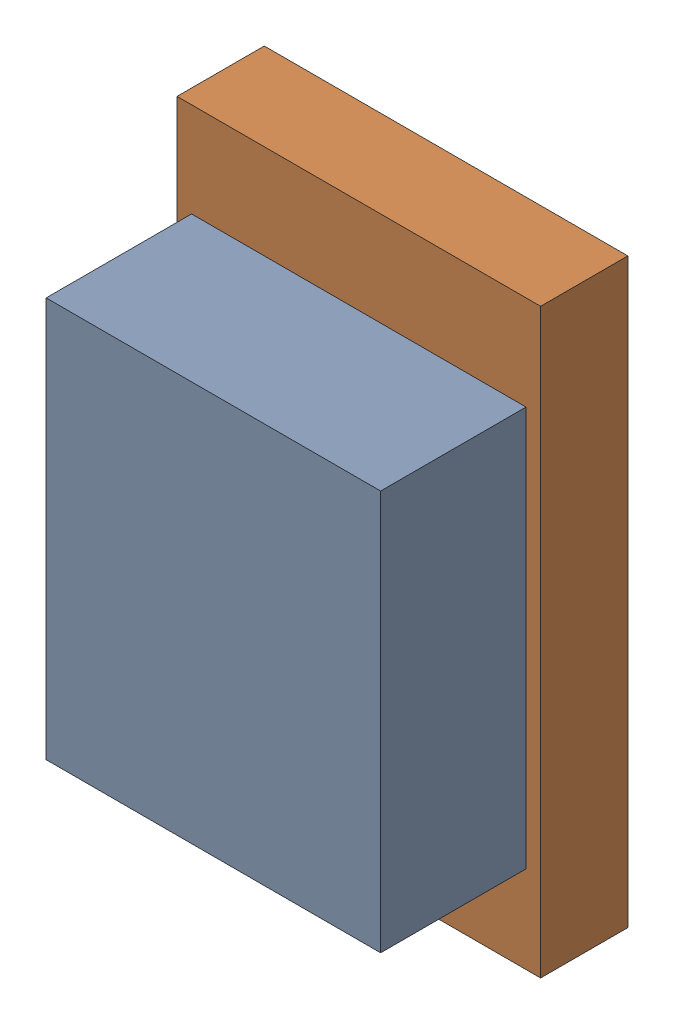
SolidWorks assembly LED2_Motor_5Kanaloa_v2.0.0_Loko, configuration Default. Lengths in mm.
Overall size (1.25 2 0.8).
4 component instances, 2 part files, 0 mates.
Components (placement in the parent):
- 334788912-1: 334788912 [Default] at (64.1477 79.2355 0) size (1.15 1.38 0.8)
  - Extruded_31-1: Extruded_31 [Default] at origin size (1.15 1.38 0.8)
- 425429200-1: 425429200 [Default] at (64.1477 79.248 0) size (1.25 2 0.3)
  - Extruded_32-1: Extruded_32 [Default] at origin size (1.25 2 0.3)
